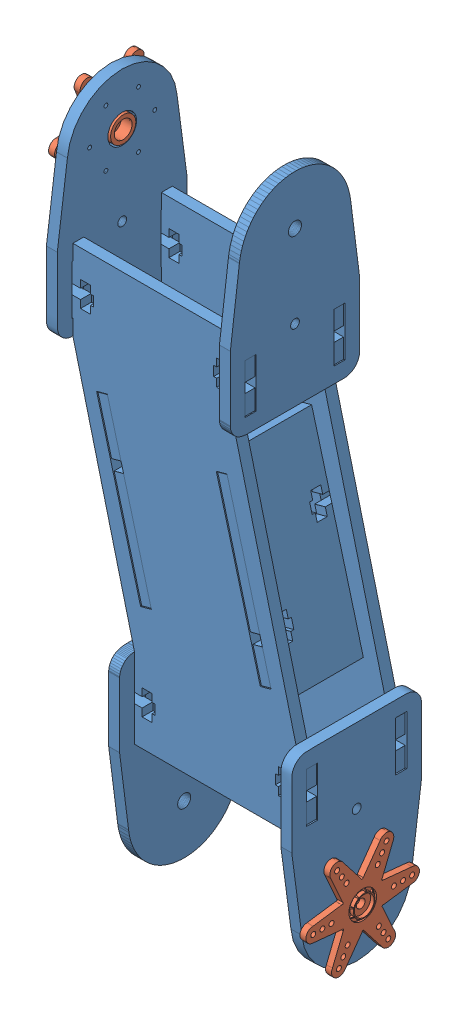
SolidWorks assembly right_thigh, configuration Default. Lengths in mm.
Overall size (83.53 224.85 48.77).
3 component instances, 2 part files, 2 mates.
Components (placement in the parent):
- right_thigh_100-1: right_thigh_100 [Default] at origin size (78.65 212.24 48.77)
- servo_arm_6_sided-1: servo_arm_6_sided [Default] at (78.3336 -23.9811 15.8745) x (0 0.855652 0.517551) z (0 0.517551 -0.855652) size (36.45 6.25 32.2)
- servo_arm_6_sided-2: servo_arm_6_sided [Default] at (-0.3182 153.2097 15.9768) x (0 -0.875448 -0.483313) z (0 0.483313 -0.875448) size (36.45 6.25 32.2)
Mates (geometry in assembly coordinates):
- ProfileCenter1: profile center anti-aligned: circle of right_thigh_100-1; circle of servo_arm_6_sided-1
- ProfileCenter2: profile center aligned: circle of right_thigh_100-1; circle of servo_arm_6_sided-2
